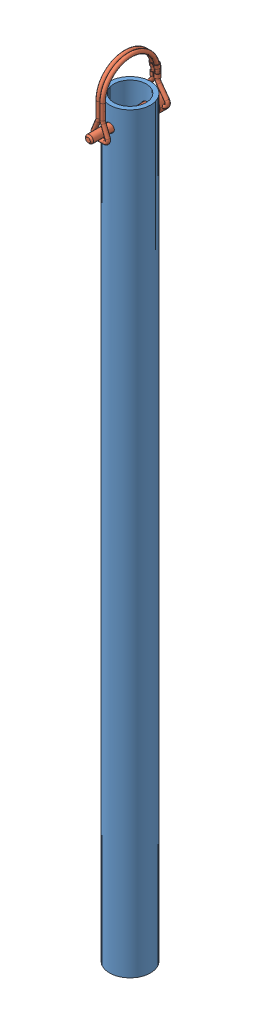
SolidWorks assembly GE-22346, configuration Default. Lengths in mm.
Overall size (33.4 639.76 58.74).
2 component instances, 2 part files, 3 mates.
Components (placement in the parent):
- GE-22347-1: GE-22347 [Default] at origin size (33.4 609.6 33.4)
- pin_,25_2.375_wirelockclevis-1: pin_,25_2.375_wirelockclevis [98416A012] at (0 593.725 4.7307) size (22.78 53.18 58.74)
Mates (geometry in assembly coordinates):
- Concentric2: concentric aligned: cylinder of Fender Pipe-1 through (0 593.725 16.7005) axis (0 0 1) radius 3.5712; cylinder of pin_,25_2.375_wirelockclevis-1 through (0 593.725 34.0995) axis (0 0 1) radius 3.175
- Tangent2: tangent anti-aligned: cylinder of Fender Pipe-1 through (0 0 0) axis (0 1 0) radius 16.7005; plane of pin_,25_2.375_wirelockclevis-1 through (0 586.9623 -16.7005) normal (0 0 1)
- Parallel2: parallel aligned: plane of pin_,25_2.375_wirelockclevis-1 through (0 593.725 4.7307) normal (1 0 0)
